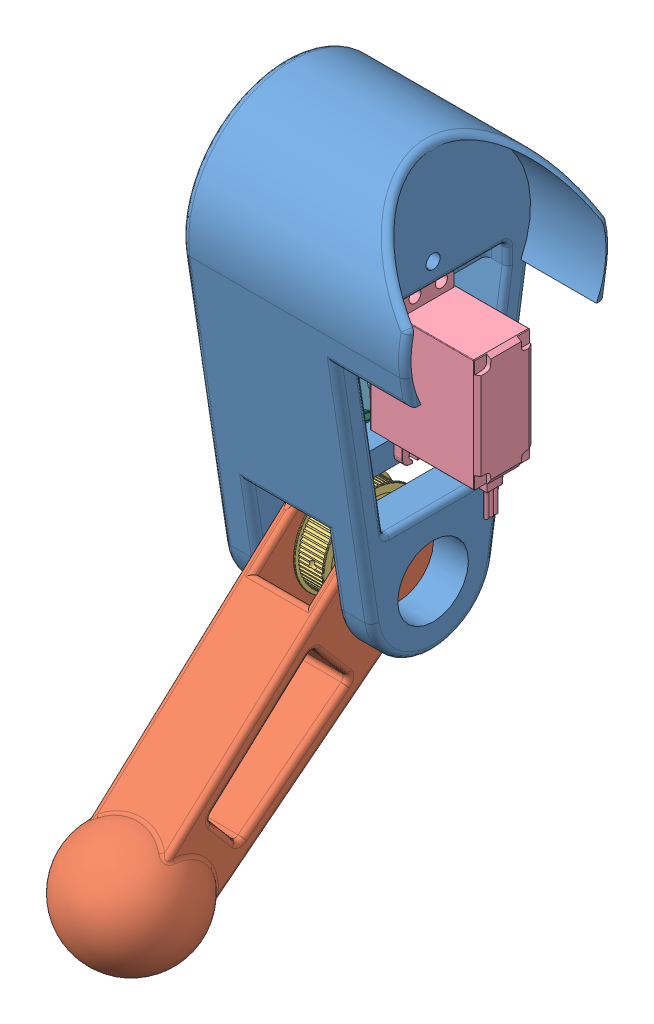
SolidWorks assembly LegDesign_v4, configuration Default. Lengths in mm.
Overall size (83.62 236.56 149.47).
6 component instances, 6 part files, 11 mates.
Components (placement in the parent):
- Thigh_4-1: Thigh_4 [Default] at (-48.9335 29.868 18.7213) size (83.62 158.88 74.17)
- Shin_4-1: Shin_4 [Default] at (-22.1365 -139.1783 100.6759) x (0 -0.762779 -0.646659) z (1 0 0) size (43.18 142.24 43.18)
- pulley1-1: pulley1 [Default] at (-33.6715 -69.775 18.7964) x (0 -1 0) z (0 0 1) size (36.5 11.5 36.5)
- sunfounder_20kgSLDPRT-2: sunfounder_20kgSLDPRT [Default] at (9.5282 -5.572 27.0019) x (0 0 -1) z (0 1 0) size (20 46.03 62.2)
- ServoHorn-1: ServoHorn [Default] at (-17.5715 -16.022 17.0019) x (0 0 -1) z (1 0 0) size (20.32 20.32 4.57)
- pulley2-1: pulley2 [Default] at (-33.6715 -16.112 17.0919) x (0 -1 0) z (0 0 1) size (29.2 9.2 29.2)
Mates (geometry in assembly coordinates):
- Concentric1: concentric aligned: circle of Thigh_4-1; circle of Shin_4-1
- Distance3: distance = 3.81 mm anti-aligned: plane of Shin_4-1 through (-12.6115 -72.6565 22.2088) normal (-1 0 0); plane of pulley1-1 through (-16.4215 -84.2 18.7213) normal (1 0 0)
- Concentric2: concentric aligned: circle of Shin_4-1; circle of pulley1-1
- Coincident2: coincident anti-aligned: plane of Thigh_4-1 through (-8.1665 -69.775 18.7964) normal (-1 0 0); plane of Shin_4-1 through (-8.1665 -72.6565 22.2088) normal (1 0 0)
- Coincident7: coincident anti-aligned: plane of Thigh_4-1 through (-118.0118 14.628 45.4483) normal (0 -1 0); plane of sunfounder_20kgSLDPRT-2 through (9.5282 14.628 7.0019) normal (0 1 0)
- Distance4: distance = 7.0019 mm anti-aligned: plane of sunfounder_20kgSLDPRT-2 through (9.5282 -5.572 7.0019) normal (0 0 -1)
- Concentric3: concentric anti-aligned: circle of sunfounder_20kgSLDPRT-2; circle of ServoHorn-1
- Coincident9: coincident anti-aligned: plane of sunfounder_20kgSLDPRT-2 through (-12.9995 -5.572 27.0019) normal (-1 0 0); plane of ServoHorn-1 through (-12.9995 -16.022 17.0019) normal (1 0 0)
- Concentric4: concentric anti-aligned: circle of ServoHorn-1; circle of pulley2-1
- Coincident10: coincident anti-aligned: plane of ServoHorn-1 through (-17.5715 -16.022 17.0019) normal (-1 0 0); plane of pulley2-1 through (-17.5715 -27.622 17.0019) normal (1 0 0)
- Coincident12: coincident aligned: plane of pulley1-1 through (-33.6715 -69.775 18.7964) normal (1 0 0); plane of pulley2-1 through (-33.6715 -16.112 17.0919) normal (1 0 0)
